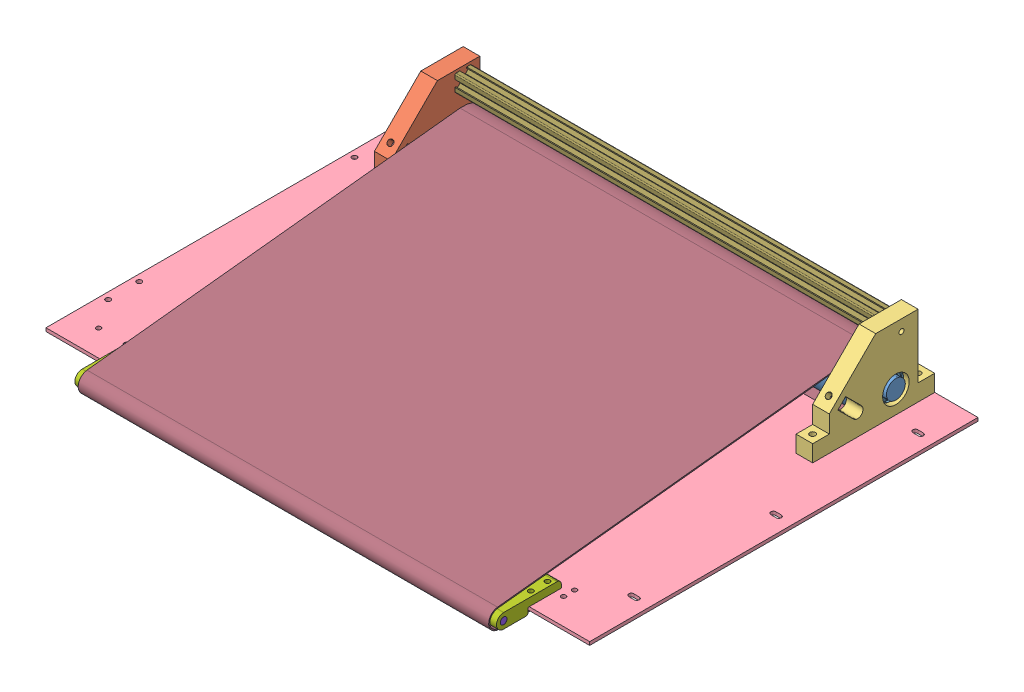
SolidWorks assembly 上床板装配体, configuration 默认. Lengths in mm.
Overall size (520.64 81.07 382.36).
22 component instances, 13 part files, 23 mates.
Components (placement in the parent):
- 传送带筒_上床板mm-1: 传送带筒_上床板mm [默认] at (-169.6408 -1.7144 460) size (481.64 50 50)
- 床板架-1: 床板架 [默认] at (-200.133 19.7148 501.199) x (0 0 -1) z (-1 0 0) size (110 72.5 15)
- 床板架 - 镜像-1: 床板架 - 镜像 [默认] at (194.867 19.6691 501.199) x (0 0 -1) z (-1 0 0) size (110 72.5 15)
- 上床板-1: 上床板 [默认] at (-256.133 -18.4789 443.5263) x (0 0 1) z (1 0 0) size (350 3 490)
- radial ball bearing_68_skf-1: radial ball bearing_68_skf [SKF - 61803 - 20,SI,NC,20_68] at (187.367 -1.7144 460) x (1 0 0) z (0 0 -1) size (5 26 26)
- radial ball bearing_68_skf-2: radial ball bearing_68_skf [SKF - 61803 - 20,SI,NC,20_68] at (-207.633 -1.7144 460) x (-1 0 0) z (0 0 1) size (5 26 26)
- 从动滚筒装配体-1: 从动滚筒装配体 [默认] at (-182.133 -18.8331 807.2203) x (0 0 1) z (1 0 0) size (60.88 17.76 280)
  - 从动滚筒滚筒_亚克力-1: 从动滚筒滚筒_亚克力 [默认] at (-9.2203 2.3813 103) size (16 16 237)
  - 从动滚筒架-1: 从动滚筒架 [默认] at (-32.9493 -0.0698 342.5) size (58.5 13 19)
  - 从动滚筒轴-1: 从动滚筒轴 [默认] at (-9.2203 2.3813 334.1374) x (0 0 -1) z (1 0 0) size (280 10 10)
  - 从动滚筒架-2: 从动滚筒架 [默认] at (-32.9493 -0.0698 81.5) size (58.5 13 19)
  - SFL678ZZ深沟球法兰杯轴承-1: SFL678ZZ深沟球法兰杯轴承 [默认] at (-9.2203 2.3813 104.4) x (0 0 -1) z (1 0 0) size (4.3 13.6 13.6)
  - SFL678ZZ深沟球法兰杯轴承-2: SFL678ZZ深沟球法兰杯轴承 [默认] at (-9.2203 2.3813 338.6) x (0 0 1) z (0.381849 0.924225 0) size (4.3 13.6 13.6)
- 从动滚筒_短装配体-1: 从动滚筒_短装配体 [默认] at (-158.2767 -23.2909 698) x (-1 0 0) z (0 0 1) size (98 17.76 60.88)
  - 从动滚筒轴_短-1: 从动滚筒轴_短 [默认] at (-28.2811 -2.0765 100) size (98 10 10)
  - 从动滚筒滚筒_短_亚克力-1: 从动滚筒滚筒_短_亚克力 [默认] at (20.8562 -2.0765 100) x (0 0 1) z (-1 0 0) size (16 16 55)
  - 从动滚筒架-1: 从动滚筒架 [默认] at (-36.6438 -4.5275 76.271) x (0 0 1) z (-1 0 0) size (58.5 13 19)
  - 从动滚筒架-2: 从动滚筒架 [默认] at (42.3562 -4.5275 76.271) x (0 0 1) z (-1 0 0) size (58.5 13 19)
  - SFL678ZZ深沟球法兰杯轴承-1: SFL678ZZ深沟球法兰杯轴承 [默认] at (-32.7438 -2.0765 100) x (-1 0 0) z (0 -0.924225 -0.381849) size (4.3 13.6 13.6)
  - SFL678ZZ深沟球法兰杯轴承-2: SFL678ZZ深沟球法兰杯轴承 [默认] at (19.4562 -2.0765 100) size (4.3 13.6 13.6)
- 1515_380mm_上床板梁-1: 1515_380mm_上床板梁 [默认] at (-200.133 40.7856 455) x (0 0 -1) z (1 0 0) size (15 15 380)
- 传送带_上床板-1: 传送带_上床板 [默认] at (174.867 -29.0352 773.7334) x (0 0.007395 -0.999973) z (-1 0 0) size (373.17 52 370)
Mates (geometry in assembly coordinates):
- 重合3: coincident: plane of 床板架-1 through (-215.133 -21.7144 535) normal (0 -1 0); plane of 上床板-1 through (233.867 -21.7144 425) normal (0 1 0)
- 重合4: coincident: plane of 床板架 - 镜像-1 through (179.867 -21.7144 535) normal (0 -1 0); plane of 上床板-1 through (233.867 -21.7144 425) normal (0 1 0)
- 同心6: concentric: cylinder of 床板架 - 镜像-1 through (189.867 -1.7144 460) axis (-1 0 0) radius 13.05; cylinder of radial ball bearing_68_skf-1 through (166.7295 -1.7144 460) axis (1 0 0) radius 13
- 重合5: coincident: plane of 床板架 - 镜像-1 through (189.867 -1.7144 460) normal (-1 0 0); plane of radial ball bearing_68_skf-1 through (189.867 -14.4144 460) normal (1 0 0)
- 同心7: concentric: cylinder of 床板架-1 through (-210.133 -1.7144 460) axis (1 0 0) radius 13; cylinder of radial ball bearing_68_skf-2 through (-186.9955 -1.7144 460) axis (-1 0 0) radius 13
- 重合6: coincident: plane of 床板架-1 through (-210.133 -1.7144 460) normal (1 0 0); plane of radial ball bearing_68_skf-2 through (-210.133 -14.4144 460) normal (-1 0 0)
- 同心8: concentric: cylinder of 传送带筒_上床板mm-1 through (-232.3467 -1.7144 460) axis (-1 0 0) radius 8.5; cylinder of radial ball bearing_68_skf-2 through (-186.9955 -1.7144 460) axis (-1 0 0) radius 8.5
- 重合7: coincident: plane of 传送带筒_上床板mm-1 through (-205.133 8.2856 460) normal (-1 0 0); plane of radial ball bearing_68_skf-2 through (-205.133 -11.5644 460) normal (1 0 0)
- 同心9: concentric: cylinder of 传送带筒_上床板mm-1 through (-232.3467 -1.7144 460) axis (-1 0 0) radius 8.5; cylinder of radial ball bearing_68_skf-1 through (166.7295 -1.7144 460) axis (1 0 0) radius 8.5
- 同心10: concentric: cylinder of 上床板-1 through (187.367 25.2856 527.5) axis (0 -1 0) radius 2.6; circle of 床板架 - 镜像-1
- 同心12: concentric: cylinder of 床板架 - 镜像-1 through (187.367 50.7856 432.5) axis (0 -1 0) radius 2.6; cylinder of 上床板-1 through (187.367 25.2856 432.5) axis (0 -1 0) radius 2.6
- 重合8: coincident: plane of 传送带筒_上床板mm-1 through (184.867 8.2856 460) normal (1 0 0); plane of radial ball bearing_68_skf-1 through (184.867 -11.5644 460) normal (-1 0 0)
- 重合9: coincident: plane of 上床板-1 through (233.867 -21.7144 425) normal (0 1 0); plane of 从动滚筒装配体-1/从动滚筒架-1 through (179.367 -21.7144 746) normal (0 -1 0)
- 同心13: concentric: cylinder of 上床板-1 through (174.867 25.2856 754) axis (0 -1 0) radius 2.25; cylinder of 从动滚筒装配体-1/从动滚筒架-1 through (174.867 -1.7144 754) axis (0 -1 0) radius 2.25
- 同心14: concentric: cylinder of 上床板-1 through (174.867 25.2856 769) axis (0 -1 0) radius 2.25; cylinder of 从动滚筒装配体-1/从动滚筒架-1 through (174.867 -1.7144 769) axis (0 -1 0) radius 2.25
- 重合12: coincident: plane of 上床板-1 through (233.867 -21.7144 425) normal (0 1 0); plane of 从动滚筒_短装配体-1/从动滚筒架-1 through (-102.633 -21.7144 746) normal (0 -1 0)
- 同心16: concentric: cylinder of 上床板-1 through (-107.133 25.2856 769) axis (0 -1 0) radius 2.25; cylinder of 从动滚筒_短装配体-1/从动滚筒架-1 through (-107.133 -1.7144 769) axis (0 -1 0) radius 2.25
- 同心17: concentric: cylinder of 上床板-1 through (-117.133 25.2856 754) axis (0 -1 0) radius 2.25; cylinder of 从动滚筒_短装配体-1/从动滚筒架-1 through (-117.133 -1.7144 754) axis (0 -1 0) radius 2.25
- 重合13: coincident: plane of 床板架 - 镜像-1 through (179.867 19.6691 501.199) normal (-1 0 0); plane of 1515_380mm_上床板梁-1 through (179.867 47.2856 461.5) normal (1 0 0)
- 同心18: concentric: cylinder of 床板架 - 镜像-1 through (179.867 40.7856 455) axis (1 0 0) radius 2.25; cylinder of 1515_380mm_上床板梁-1 through (179.867 40.7856 455) axis (-1 0 0) radius 1.65
- 同心19: concentric: cylinder of 传送带筒_上床板mm-1 through (-232.3467 -1.7144 460) axis (-1 0 0) radius 25; cylinder of 传送带_上床板-1 through (-195.133 -1.7144 460) axis (1 0 0) radius 25
- 重合15: coincident: plane of 传送带_上床板-1 through (-195.133 -29.2145 797.9789) normal (0 0.999973 0.007395); plane of assembly through (0 -23.3121 -0.1724) normal (0 -0.999973 -0.007395)
- 重合16: coincident: plane of 传送带筒_上床板mm-1 through (-195.133 23.2856 460) normal (-1 0 0); plane of 传送带_上床板-1 through (-195.133 -1.7144 460) normal (-1 0 0)
